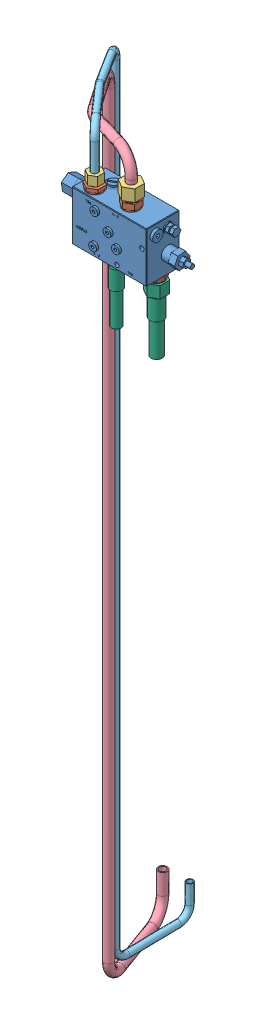
SolidWorks assembly Regenereringsventil_kpl, configuration Default. Lengths in mm.
Overall size (321.5 1465 311).
14 component instances, 7 part files, 27 mates.
Components (placement in the parent):
- 59044-1: 59044 [Default] at origin size (227 93 64)
- Lige_forskr_kpl-1: Lige_forskr_kpl [1-2" - 12 mm] at (24 99 43) x (1 0 0) z (0 -1 0) size (27 31.18 40.5)
  - Lige forskruninger-1: Lige forskruninger [P-GES 12 LR 1-2 - WD - 25108] at origin size (27 31.18 34)
  - Omløber-1: Omløber [M 12 L - 25183] at (0 0 -2) x (-1 0 0) z (0 0 -1) size (22 25.4 15.5)
- Lige_forskr_kpl-2: Lige_forskr_kpl [1-2" - 16 mm] at (84 103 37) x (1 0 0) z (0 -1 0) size (30 34.64 52.4)
  - Lige forskruninger-1: Lige forskruninger [P-GEV 16 SR-WD - 26334] at origin size (27 31.18 41)
  - Omløber-1: Omløber [M 16 S - 26338] at (0 0 -4) x (-1 0 0) z (0 0 -1) size (30 34.64 21.4)
- 6344641-1: 6344641 [Default] at (84 108.5 37) x (0 1 0) z (0 0 1) size (1447.5 235.5 292)
- 6344642-1: 6344642 [Default] at (24 103 43) x (0 1 0) z (0 0 1) size (1443 123 294)
- Lige forskruninger-1: Lige forskruninger [P-GEV 16 SR-WD - 26334] at (113.5 -13 21) x (0.866025 0 0.5) z (0 1 0) size (27 31.18 41)
- Lige forskruninger-2: Lige forskruninger [P-GES 12 LR 1-2 - WD - 25108] at (41 -9 21) x (0.866025 0 0.5) z (0 1 0) size (27 31.18 34)
- Slange ende lige-1: Slange ende lige [3-8] at (41 -12 21) x (1 0 0) z (0 -1 0) size (22 25.4 114)
- Slange ende lige-2: Slange ende lige [1-2] at (113.5 -16 21) x (1 0 0) z (0 -1 0) size (30 34.64 120)
- Holder_ide_1-1: Holder_ide_1 [Default] at (198 -1 -6) x (0 1 0) z (0 0 1) (suppressed, hidden)
Mates (geometry in assembly coordinates):
- Concentric1: concentric aligned: cylinder of 59044-1 through (24 48 43) axis (0 1 0) radius 9.5; cylinder of Lige_forskr_kpl-1/Lige forskruninger-1 through (24 76 43) axis (0 1 0) radius 10.4975
- Coincident1: coincident anti-aligned: plane of 59044-1 through (0 90 60) normal (0 1 0); plane of Lige_forskr_kpl-1/Lige forskruninger-1 through (24 90 43) normal (0 -1 0)
- Concentric2: concentric aligned: cylinder of 59044-1 through (84 48 37) axis (0 1 0) radius 9.5; cylinder of Lige_forskr_kpl-2/Lige forskruninger-1 through (84 76 37) axis (0 1 0) radius 10.4775
- Coincident2: coincident anti-aligned: plane of 59044-1 through (0 90 60) normal (0 1 0); plane of Lige_forskr_kpl-2/Lige forskruninger-1 through (84 90 37) normal (0 -1 0)
- Parallel1: parallel aligned: plane of Lige_forskr_kpl-2 through (84 103 37) normal (0 0 1); plane of assembly through (0 0 0) normal (0 0 1)
- Parallel2: parallel aligned: plane of Lige_forskr_kpl-1 through (24 99 43) normal (0 0 1); plane of assembly through (0 0 0) normal (0 0 1)
- Parallel3: parallel aligned: plane of 6344641-1 through (84 108.5 37) normal (0 0 1); plane of assembly through (0 0 0) normal (0 0 1)
- Coincident7: coincident anti-aligned: plane of Lige_forskr_kpl-2/Lige forskruninger-1 through (84 108.5 45) normal (0 1 0); plane of 6344641-1 through (84 108.5 37) normal (0 -1 0)
- Concentric4: concentric aligned: cylinder of Lige_forskr_kpl-2/Lige forskruninger-1 through (84 103 37) axis (0 -1 0) radius 8; cylinder of 6344641-1 through (84 135.5 37) axis (0 -1 0) radius 8
- Concentric5: concentric anti-aligned: cylinder of Lige_forskr_kpl-1/Omløber-1 through (24 101 43) axis (0 1 0) radius 6; cylinder of 6344642-1 through (24 167 43) axis (0 -1 0) radius 6
- Coincident8: coincident anti-aligned: plane of Lige_forskr_kpl-1/Lige forskruninger-1 through (24 103 49) normal (0 1 0); plane of 6344642-1 through (24 103 43) normal (0 -1 0)
- Parallel4: parallel aligned: plane of 6344642-1 through (24 103 43) normal (0 0 1); plane of assembly through (0 0 0) normal (0 0 1)
- Concentric6: concentric aligned: cylinder of 59044-1 through (113.5 42 21) axis (0 -1 0) radius 9.5; cylinder of Lige forskruninger-1 through (113.5 14 21) axis (0 -1 0) radius 10.4775
- Coincident9: coincident anti-aligned: plane of 59044-1 through (0 0 60) normal (0 -1 0); plane of Lige forskruninger-1 through (113.5 0 21) normal (0 1 0)
- Parallel5: parallel aligned: plane of 59044-1 through (0 90 60) normal (0 0 1); plane of Lige forskruninger-1 through (105.7058 -3 34.5) normal (0 0 1)
- Concentric7: concentric aligned: cylinder of 59044-1 through (41 42 21) axis (0 -1 0) radius 9.5; cylinder of Lige forskruninger-2 through (41 14 21) axis (0 -1 0) radius 10.4975
- Coincident10: coincident anti-aligned: plane of 59044-1 through (0 0 60) normal (0 -1 0); plane of Lige forskruninger-2 through (41 0 21) normal (0 1 0)
- Parallel6: parallel aligned: plane of 59044-1 through (0 90 0) normal (0 0 -1); plane of Lige forskruninger-2 through (48.7942 -3 7.5) normal (0 0 -1)
- Concentric8: concentric aligned: cylinder of Lige forskruninger-2 through (41 -20 21) axis (0 1 0) radius 9; cylinder of Slange ende lige-1 through (41 -24 21) axis (0 1 0) radius 8.331
- Distance1: distance = 3 mm anti-aligned: plane of Lige forskruninger-2 through (41 -9 -6) normal (0 -1 0); plane of Slange ende lige-1 through (41 -12 33.7017) normal (0 1 0)
- Concentric9: concentric aligned: cylinder of Lige forskruninger-1 through (113.5 -27 21) axis (0 1 0) radius 12; cylinder of Slange ende lige-2 through (113.5 -76 21) axis (0 1 0) radius 12
- Distance2: distance = 3 mm anti-aligned: plane of Lige forskruninger-1 through (113.5 -13 -6) normal (0 -1 0); plane of Slange ende lige-2 through (98.5 -16 46.9808) normal (0 1 0)
- Coincident23: coincident anti-aligned: plane of 59044-1 through (0 90 0) normal (0 0 -1); plane of assembly through (126 56 0) normal (0 0 1)
- Concentric19: concentric anti-aligned: cylinder of 59044-1 through (126 56 60) axis (0 0 1) radius 4; cylinder of assembly through (126 56 0) axis (0 0 -1) radius 3.4
- Parallel8: parallel aligned: plane of 59044-1 through (0 0 60) normal (0 -1 0); plane of assembly through (198 -1 0) normal (0 -1 0)
- Parallel9: parallel aligned: plane of Slange ende lige-2 through (113.5 -16 21) normal (0 0 1); plane of assembly through (0 0 0) normal (0 0 1)
- Parallel10: parallel aligned: plane of Slange ende lige-1 through (41 -12 21) normal (0 0 1); plane of assembly through (0 0 0) normal (0 0 1)
